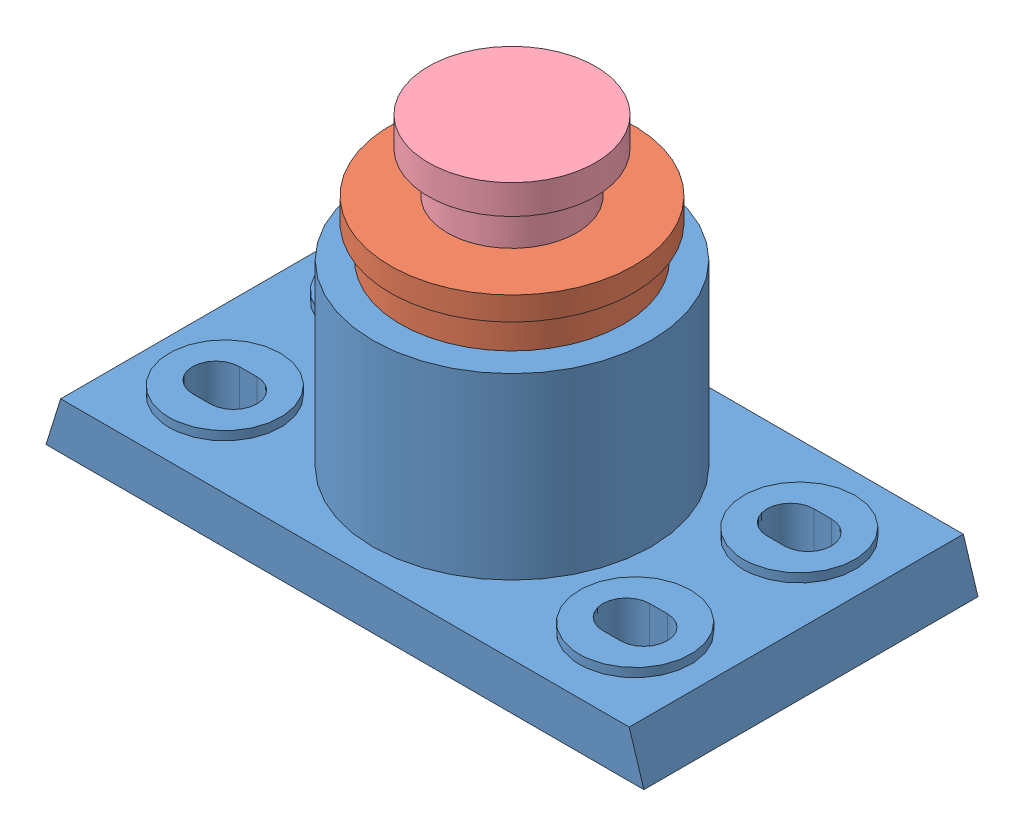
SolidWorks assembly assembly2, configuration Default. Lengths in mm.
Overall size (204 120 114).
4 component instances, 4 part files, 8 mates.
Components (placement in the parent):
- body CI-1: body CI [Default] at (6.4439 65.8995 205.6382) size (204 77 114)
- bush-1: bush [Default] at (6.4439 68.8995 205.6382) x (0 0 -1) z (1 0 0) size (83 77 83)
- Pad-1: Pad [Default] at (6.4439 68.8995 205.6382) size (44 16 44)
- shaft-2: shaft [Default] at (6.4439 84.8995 205.6382) x (0.998247 0 0.059194) z (-0.059194 0 0.998247) size (57 85 57)
Mates (geometry in assembly coordinates):
- Concentric1: concentric aligned: cylinder of body CI-1 through (6.4439 184.8213 205.6382) axis (0 1 0) radius 32.5; cylinder of bush-1 through (6.4439 167.217 205.6382) axis (0 1 0) radius 29.5
- Concentric2: concentric anti-aligned: cylinder of body CI-1 through (-15.5561 49.8995 205.6382) axis (0 1 0) radius 1.5; cylinder of bush-1 through (-15.5561 78.8995 205.6382) axis (0 -1 0) radius 1.5
- Concentric3: concentric anti-aligned: cylinder of body CI-1 through (-15.5561 49.8995 205.6382) axis (0 1 0) radius 1.5; cylinder of Pad-1 through (-15.5561 78.8995 205.6382) axis (0 -1 0) radius 1.5
- Coincident3: coincident anti-aligned: plane of body CI-1 through (53.9439 126.8995 205.6382) normal (0 1 0); plane of bush-1 through (6.4439 126.8995 174.6382) normal (0 -1 0)
- Concentric5: concentric anti-aligned: cylinder of bush-1 through (6.4439 68.8995 205.6382) axis (0 1 0) radius 22; cylinder of Pad-1 through (6.4439 68.8995 205.6382) axis (0 -1 0) radius 22
- Concentric6: concentric anti-aligned: cylinder of bush-1 through (6.4439 68.8995 205.6382) axis (0 1 0) radius 22; cylinder of shaft-2 through (6.4439 275.545 205.6382) axis (0 -1 0) radius 22
- Coincident4: coincident aligned: plane of bush-1 through (6.4439 68.8995 205.6382) normal (0 -1 0); plane of Pad-1 through (6.4439 68.8995 205.6382) normal (0 -1 0)
- Coincident5: coincident: point of Pad-1; plane of shaft-2 through (6.4439 84.8995 205.6382) normal (0 -1 0)
